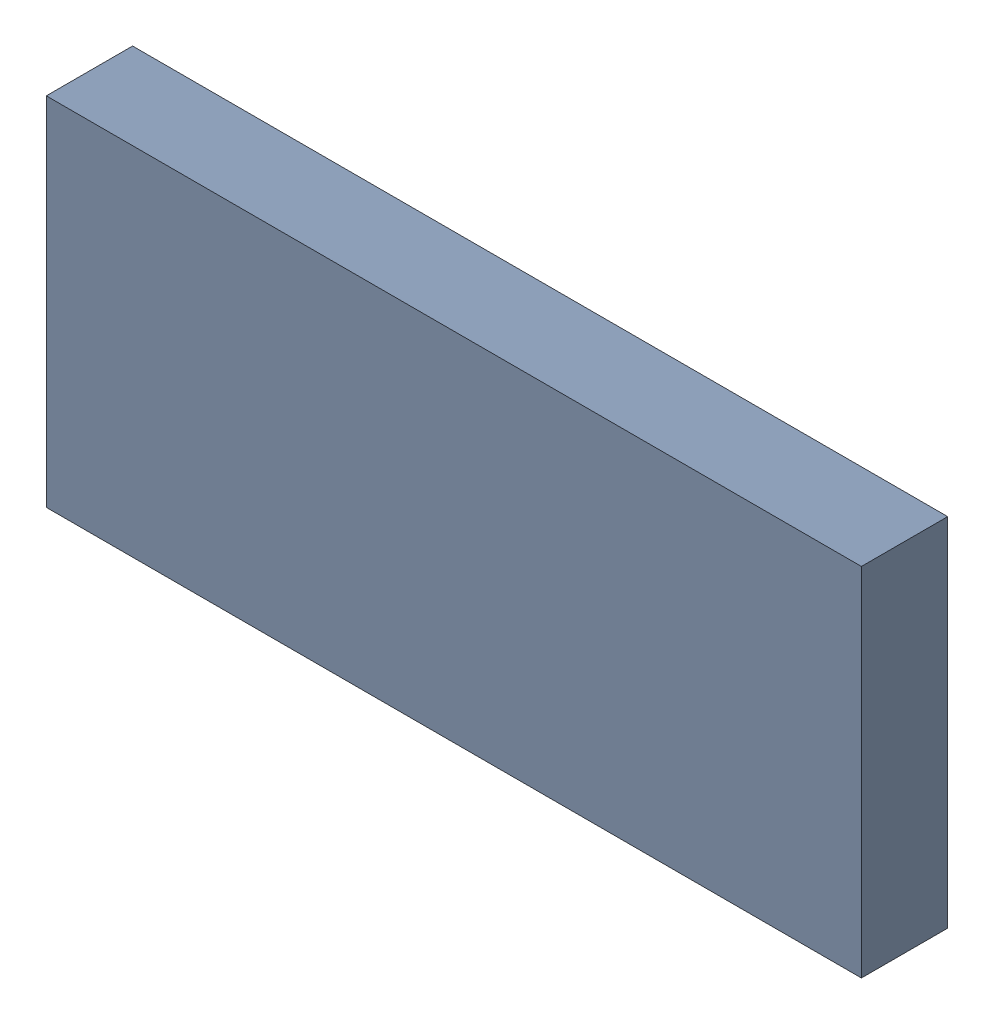
SolidWorks assembly 6327399616, configuration Default. Lengths in mm.
Overall size (2.4 1.05 0.25).
2 component instances, 1 part files, 0 mates.
Components (placement in the parent):
- 6701982208-1:  [Default] at (27.7 14.8 0) (suppressed, hidden)
- Extruded-10-1: Extruded-10 [Default] at origin size (2.4 1.05 0.25)
